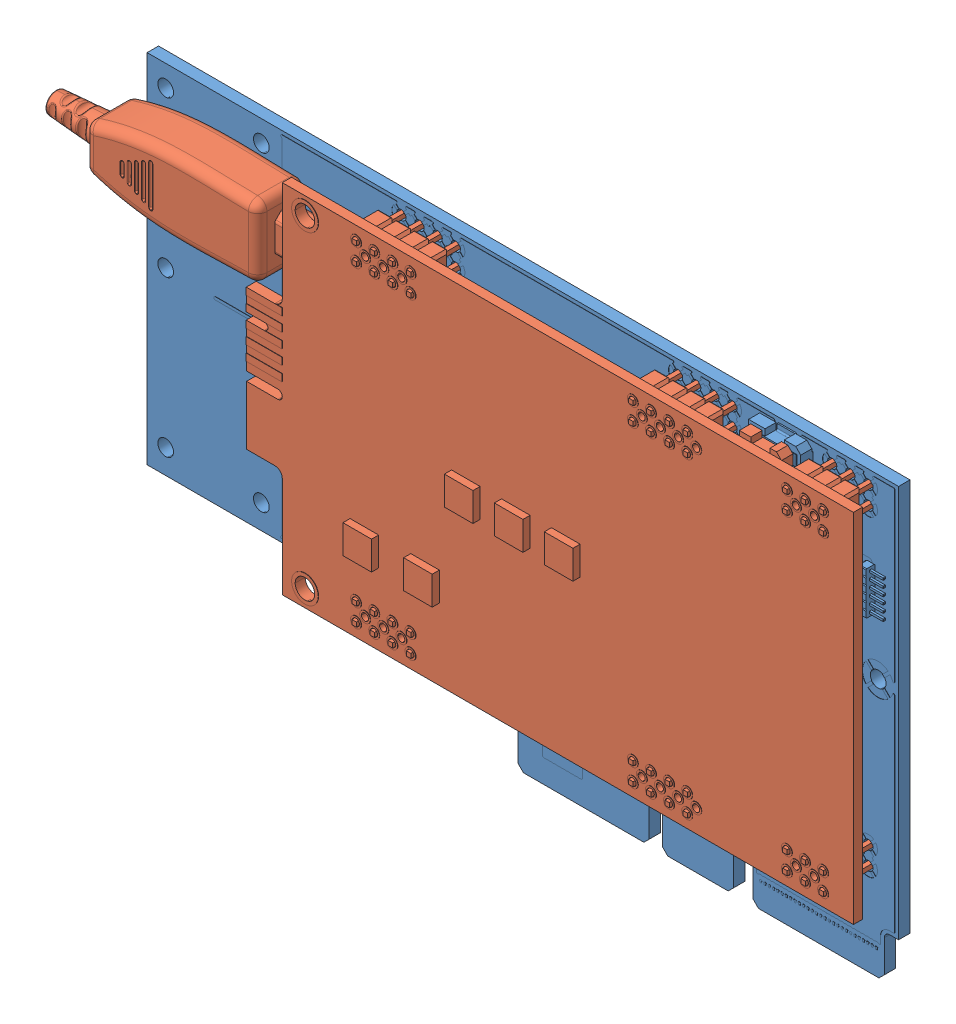
SolidWorks assembly 1xCardAdapter, configuration Default. Lengths in mm.
Overall size (114.47 61 10.4).
2 component instances, 2 part files, 4 mates.
Components (placement in the parent):
- HYDRA_VMM3_CARD-1: HYDRA_VMM3_CARD [Default] at (37.8026 54.1071 80.2687) size (105.25 61 6.02)
- VMM3Hybrid_Reworked-1: VMM3Hybrid_Reworked [Default] at (90.3748 34.5693 88.1363) x (-1 0 0) z (0 0 -1) size (114.42 50 10.4)
Mates (geometry in assembly coordinates):
- Parallel1: parallel: plane of HYDRA_VMM3_CARD-1 through (37.8026 54.1071 81.8687) normal (0 0 1); plane of VMM3Hybrid_Reworked-1 through (90.3748 34.5693 191.4512) normal (0 0 -1)
- Concentric1: concentric: circle of HYDRA_VMM3_CARD-1; circle of VMM3Hybrid_Reworked-1
- Parallel2: parallel: plane of HYDRA_VMM3_CARD-1 through (-14.8224 84.6071 80.2687) normal (0 1 0); plane of VMM3Hybrid_Reworked-1 through (90.3748 84.5693 191.4512) normal (0 1 0)
- Coincident3: coincident anti-aligned: plane of HYDRA_VMM3_CARD-1 through (75.9718 45.9343 85.1363) normal (0 0 1); plane of VMM3Hybrid_Reworked-1 through (75.9768 49.4693 85.1363) normal (0 0 -1)
